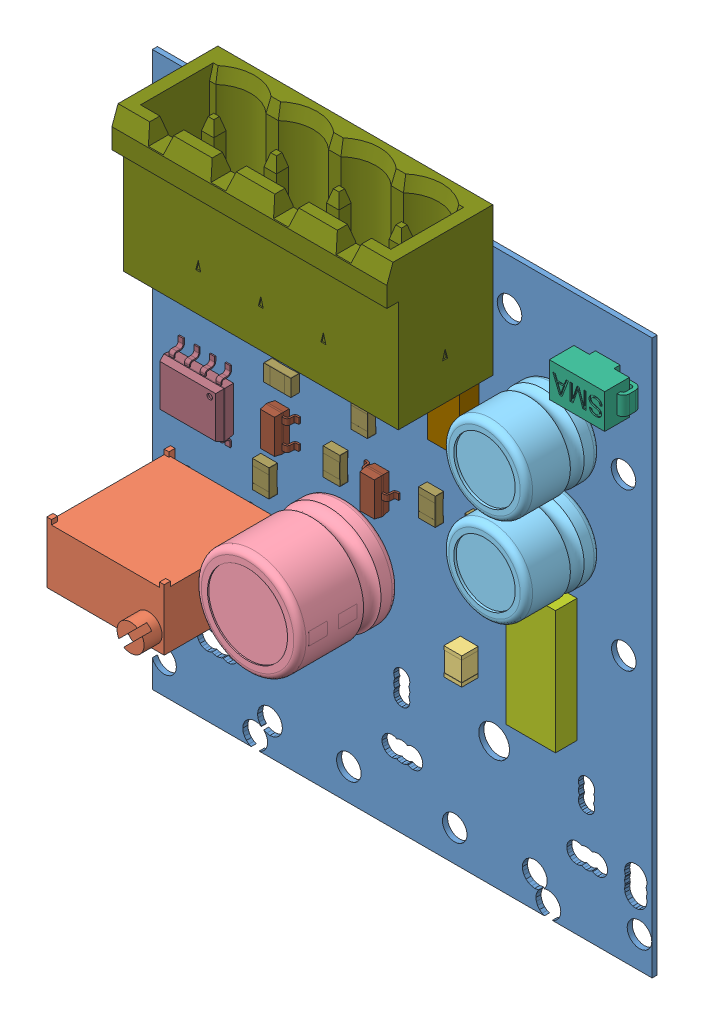
SolidWorks assembly 3dcar, configuration Default. Lengths in mm.
Overall size (40.58 47.9 15.09).
63 component instances, 16 part files, 0 mates.
Components (placement in the parent):
- Board-1: Board [Default] at (-0.7271 0.0984 0) size (40.58 45 0.41)
- TR1-1: TR1 [Default] at origin size (9.53 4.96 14.91)
  - TRIM_BOURNS_3296Y-1: TRIM_BOURNS_3296Y [Default] at (5.4999 -29.5001 0) x (-1 0 0) z (0 0 1) size (9.53 4.96 14.91)
- C1-1: C1 [Default] at origin size (1.45 2.2 1.35)
  - CAP_0805-1: CAP_0805 [Default] at (25.0001 -29.7501 -0.013) x (0 -1 0) z (0 0 1) size (2.2 1.45 1.35)
- C2-1: C2 [Default] at origin size (8.5 8.5 11.6)
  - CAPPR350-850X800-1: CAPPR350-850X800 [Default] at (15.0001 -27.7499 0) x (1 0 0) z (0 0 1) size (8.5 8.5 11.6)
- C3-1: C3 [Default] at origin size (6.8 6.8 9.6)
  - CAPPR250-680X600-1: CAPPR250-680X600 [Default] at (32.24 -9.99 0) x (0 -1 0) z (0 0 1) size (6.8 6.8 9.6)
- C4-1: C4 [Default] at origin size (6.8 6.8 9.6)
  - CAPPR250-680X600-1: CAPPR250-680X600 [Default] at (32.24 -17.24 0) x (0 -1 0) z (0 0 1) size (6.8 6.8 9.6)
- C5-1: C5 [Default] at origin size (2.2 1.45 1.35)
  - CAP_0805-1: CAP_0805 [Default] at (3.4999 -16.9999 -0.3985) x (-1 0 0) z (0 0 -1) size (2.2 1.45 1.35)
- D1-1: D1 [Default] at origin size (5.5 2.8 2.5)
  - DO214AA-1: DO214AA [Default] at (36.2499 -4.5001 0) x (-1 0 0) z (0 0 1) size (5.5 2.8 2.5)
- D2-1: D2 [Default] at origin size (5.5 2.8 2.5)
  - DO214AA-1: DO214AA [Default] at (16.4999 -12.0001 0) x (-1 0 0) z (0 0 1) size (5.5 2.8 2.5)
- HC1-1: HC1 [Default] at origin size (4 10 1.75)
  - 1540841040-1: 1540841040 [Default] at (31.75 -26.25 0) size (4 10 1.75)
    - Extruded-1: Extruded [Default] at origin size (4 10 1.75)
- LD1-1: LD1 [Default] at origin size (1.6 3.3 1)
  - LED_AVAGO_HSMC-C110-1: LED_AVAGO_HSMC-C110 [Default] at (1.9999 -11.7499 0) x (0 1 0) z (0 0 1) size (3.3 1.6 1)
- LDO1-1: LDO1 [Default] at origin size (2.6 4.6 1.6)
  - 1540841176-1: 1540841176 [Default] at (24.5 -12.25 0) size (2.6 4.6 1.6)
    - Extruded_2-1: Extruded_2 [Default] at origin size (2.6 4.6 1.6)
- Q1-1: Q1 [Default] at origin size (4 5 1.75)
  - 1540840904-1: 1540840904 [Default] at (16.75 -16.5 -2.1615) size (4 5 1.75)
    - Extruded_3-1: Extruded_3 [Default] at origin size (4 5 1.75)
- Q2-1: Q2 [Default] at origin size (2.8 2.9 1.3)
  - SOT23-3-1: SOT23-3 [Default] at (18.0001 -21.2501 -0.0127) x (0 -1 0) z (0 0 1) size (2.9 2.8 1.3)
- Q3-1: Q3 [Default] at origin size (2.8 2.9 1.3)
  - SOT23-3-1: SOT23-3 [Default] at (9.8999 -20.8999 -0.0127) x (0 1 0) z (0 0 1) size (2.9 2.8 1.3)
- R1-1: R1 [Default] at origin size (2.2 1.35 0.7)
  - RES_0805_(2012_metric)-1: RES_0805_(2012_metric) [Default] at (5.0999 -13.5001 -0.013) x (-1 0 0) z (0 0 1) size (2.2 1.35 0.7)
- R2-1: R2 [Default] at origin size (1.35 2.2 0.7)
  - RES_0805_(2012_metric)-1: RES_0805_(2012_metric) [Default] at (8.7499 -24.9999 -0.013) x (0 1 0) z (0 0 1) size (2.2 1.35 0.7)
- R3-1: R3 [Default] at origin size (1.35 2.2 0.7)
  - RES_0805_(2012_metric)-1: RES_0805_(2012_metric) [Default] at (8.4999 -15.5001 -0.3985) x (0 -1 0) z (0 0 -1) size (2.2 1.35 0.7)
- R4-1: R4 [Default] at origin size (1.35 2.2 0.7)
  - RES_0805_(2012_metric)-1: RES_0805_(2012_metric) [Default] at (11.0001 -15.4999 -0.3985) x (0 1 0) z (0 0 -1) size (2.2 1.35 0.7)
- R5-1: R5 [Default] at origin size (1.35 2.2 0.7)
  - RES_0805_(2012_metric)-1: RES_0805_(2012_metric) [Default] at (22.2499 -20.2499 -0.013) x (0 1 0) z (0 0 1) size (2.2 1.35 0.7)
- R6-1: R6 [Default] at origin size (2.2 1.35 0.7)
  - RES_0805_(2012_metric)-1: RES_0805_(2012_metric) [Default] at (10.0999 -17.4001 -0.013) x (-1 0 0) z (0 0 1) size (2.2 1.35 0.7)
- R7-1: R7 [Default] at origin size (1.35 2.2 0.7)
  - RES_0805_(2012_metric)-1: RES_0805_(2012_metric) [Default] at (8.5001 -18.7999 -0.3985) x (0 1 0) z (0 0 -1) size (2.2 1.35 0.7)
- R8-1: R8 [Default] at origin size (1.35 2.2 0.7)
  - RES_0805_(2012_metric)-1: RES_0805_(2012_metric) [Default] at (16.7501 -16.7501 -0.013) x (0 -1 0) z (0 0 1) size (2.2 1.35 0.7)
- R9-1: R9 [Default] at origin size (1.35 2.2 0.7)
  - RES_0805_(2012_metric)-1: RES_0805_(2012_metric) [Default] at (14.4999 -21.2499 -0.013) x (0 1 0) z (0 0 1) size (2.2 1.35 0.7)
- R10-1: R10 [Default] at origin size (2.2 1.35 0.7)
  - RES_0805_(2012_metric)-1: RES_0805_(2012_metric) [Default] at (3.0001 -21.7501 -0.3985) x (1 0 0) z (0 0 -1) size (2.2 1.35 0.7)
- R11-1: R11 [Default] at origin size (1.35 2.2 0.7)
  - RES_0805_(2012_metric)-1: RES_0805_(2012_metric) [Default] at (26.0001 -20.2501 -0.013) x (0 -1 0) z (0 0 1) size (2.2 1.35 0.7)
- U2-1: U2 [Default] at origin size (4.9 5.78 1.45)
  - SW3DPS-SO-8-DEFAULT-1: SW3DPS-SO-8-DEFAULT [Default] at (5.4873 -19.1333 0) x (0 -1 0) z (-1 0 0) size (5.78 1.45 4.9)
- AMS1-1: AMS1 [Default] at origin size (6.7 7.3 1.8)
  - SOT223-4-1: SOT223-4 [Default] at (25.0001 -16.0001 -0.4115) x (1 0 0) z (0 0 -1) size (6.7 7.3 1.8)
- U3-1: U3 [Default] at origin size (4.5 5.1 1.2)
  - 1540840768-1: 1540840768 [Default] at (31.5 -27 -1.6115) size (4.5 5.1 1.2)
    - Extruded_4-1: Extruded_4 [Default] at origin size (4.5 5.1 1.2)
- J1-1: J1 [Default] at origin size (22.32 12 12.1)
  - PHOENIX_1757268-1: PHOENIX_1757268 [Default] at (15.75 -7.0001 0) x (-1 0 0) z (0 0 1) size (22.32 12 12.1)
